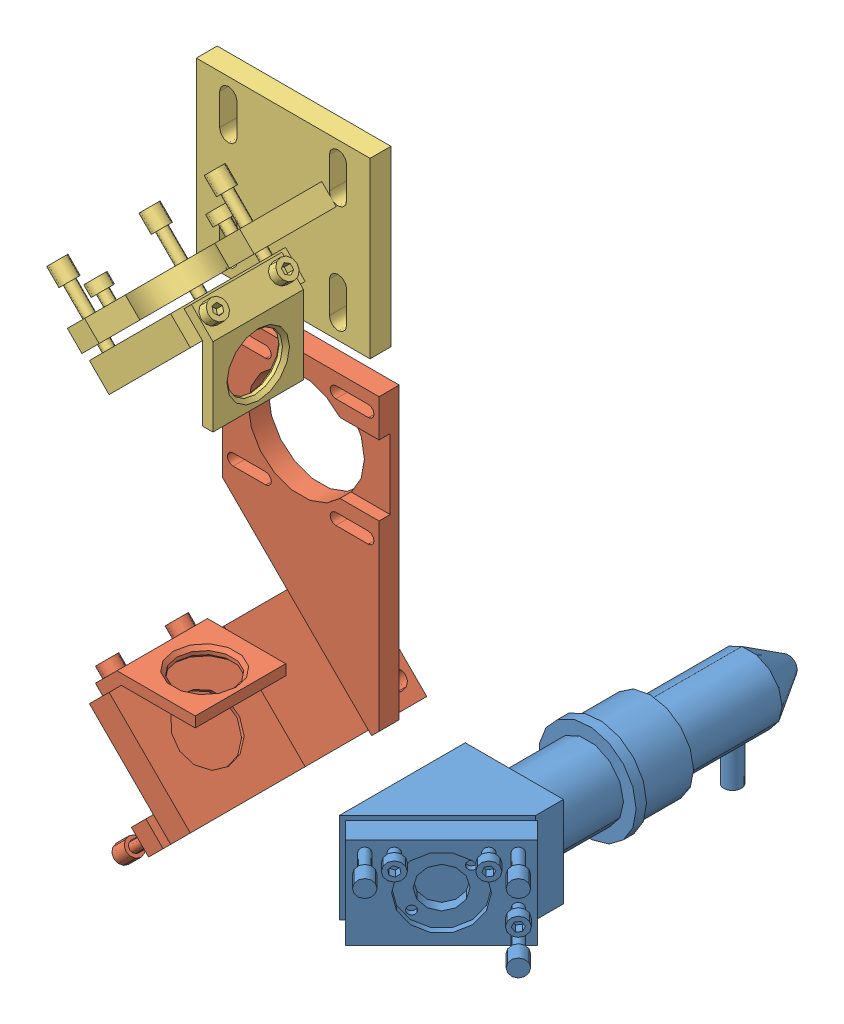
SolidWorks assembly Assem1, configuration Default. Lengths in mm.
Overall size (132.57 164.59 128.17).
3 component instances, 3 part files, 4 mates.
Components (placement in the parent):
- cloudray laser head-1: cloudray laser head [Default] at origin size (42.55 35.44 128.17)
- cloudray laser 2nd mirror-1: cloudray laser 2nd mirror [Default] at (-67.4641 0 21.5) x (1 0 0) z (0 -1 0) size (49.03 75.75 97.33)
- cloudray laser 1st mirror-1: cloudray laser 1st mirror [Default] at (-67.4641 98.8261 21.5) x (0 -1 0) z (-1 0 0) size (49.9 55.75 50.63)
Mates (geometry in assembly coordinates):
- Coincident1: coincident anti-aligned: plane of cloudray laser head-1 through (0 0 21.5) normal (0 0 -1); plane of cloudray laser 2nd mirror-1 through (-67.4641 0 21.5) normal (0 0 1)
- Coincident2: coincident aligned: plane of cloudray laser 2nd mirror-1 through (-67.4641 0 21.5) normal (0 0 1); plane of cloudray laser 1st mirror-1
- Coincident4: coincident anti-aligned: plane of cloudray laser 2nd mirror-1; plane of cloudray laser 1st mirror-1 through (-67.4641 98.8261 21.5) normal (-1 0 0)
- Coincident5: coincident anti-aligned: plane of cloudray laser head-1 through (0 0 0) normal (0 1 0); plane of cloudray laser 2nd mirror-1 through (-67.4641 0 21.5) normal (0 -1 0)
